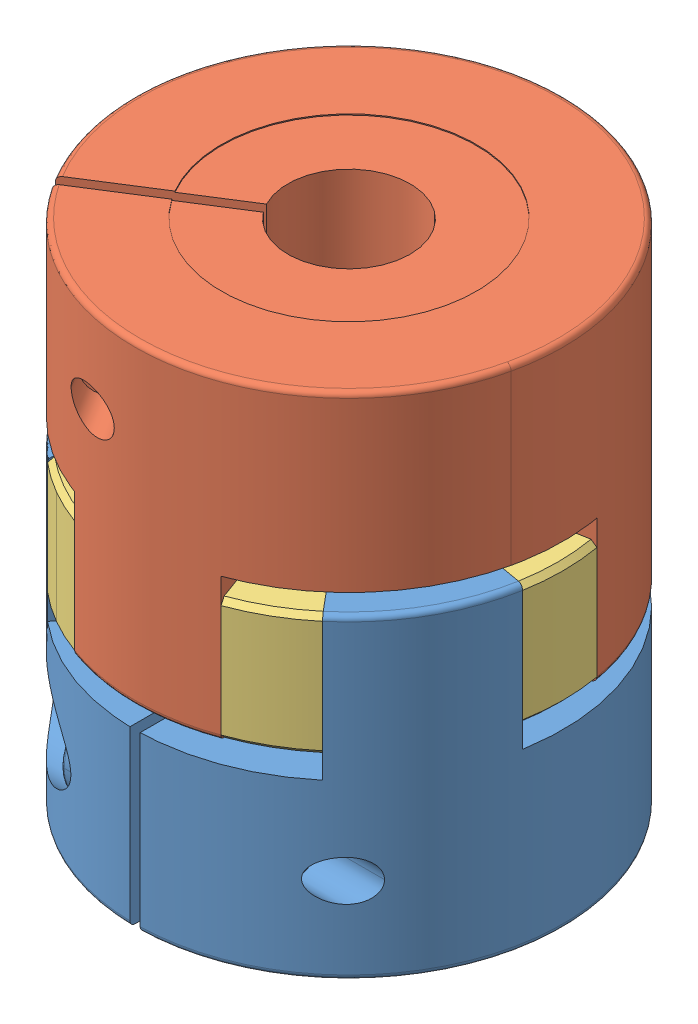
SolidWorks assembly sprzeglo ekl 19 12, configuration Domyślna. Lengths in mm.
Overall size (83.78 50.01 62.16).
4 component instances, 3 part files, 0 mates.
Components (placement in the parent):
- EKL_Size20.STEP-1: EKL_Size20.STEP [Domyślna] at (-9.446 -23.7001 80.7595) size (83.78 50.01 62.16)
  - 3D_EKL_020_Nabe1.STEP-1: 3D_EKL_020_Nabe1.STEP [Domyślna] at origin size (83.78 31.01 42)
  - 3D_EKL_020_Nabe2.STEP-1: 3D_EKL_020_Nabe2.STEP [Domyślna] x (0.218377 0 -0.975864) z (0.975864 0 0.218377) size (51.25 31.01 42.01)
  - 3D_EKL_020_Stern.STEP-1: 3D_EKL_020_Stern.STEP [Domyślna] x (0.866025 0 0.5) z (-0.5 0 0.866025) size (39.47 12 42)
